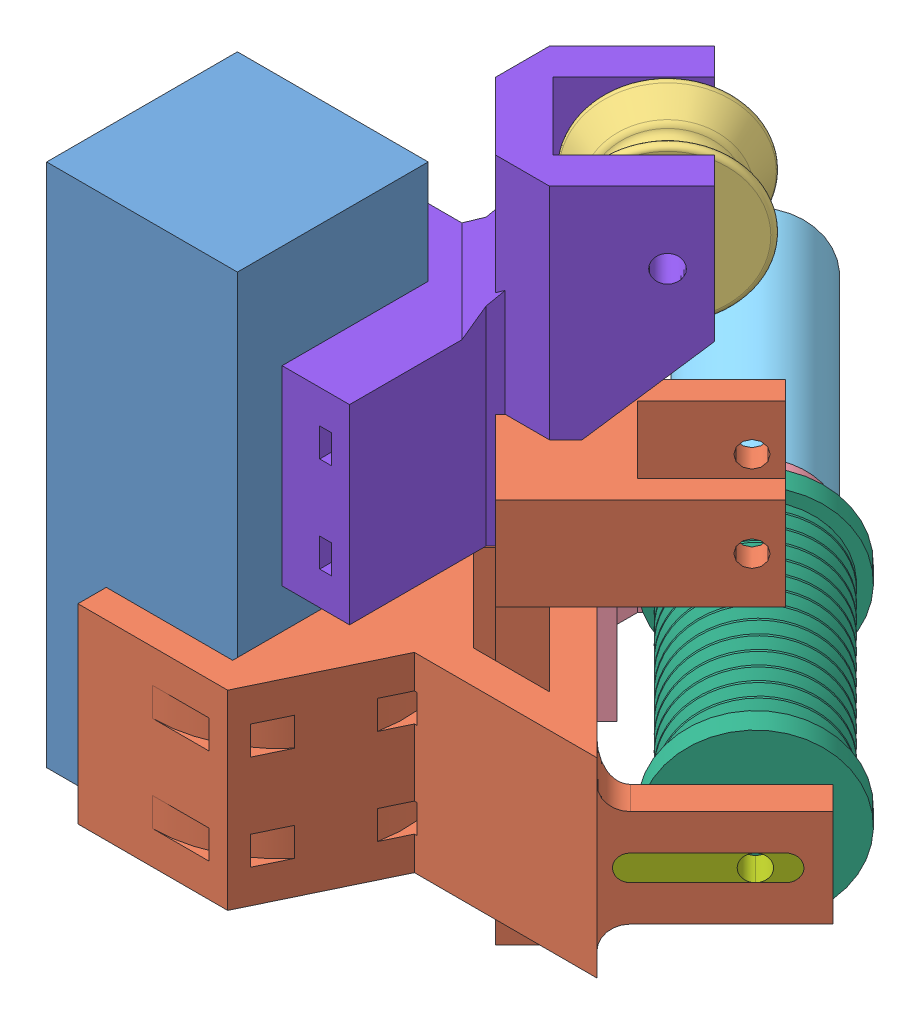
SolidWorks assembly SecondimprvedMechanism, configuration Default. Lengths in mm.
Overall size (306.23 131.11 265.8).
8 component instances, 8 part files, 15 mates.
Components (placement in the parent):
- tableLeg-1: tableLeg [Default] at (50.0377 26.8176 100.477) size (40 110 40)
- square With wire directionalSmaller SecondSupport-1: square With wire directionalSmaller SecondSupport [Default] at (43.5377 46.8176 100.977) size (298.83 105.47 258.03)
- Improvedpulley-1: Improvedpulley [Default] at (89.1192 130.1429 49.3747) x (0.707107 0 0.707107) z (-0.466203 0.751871 0.466203) size (18 32.63 32.63)
- braket-1: braket [Default] at (73.443 44.8547 48.5147) x (0.707107 0 0.707107) z (0 1 0) size (34 36.5 26)
- DC MOTOR-1: DC MOTOR [Default] at (33.1379 44.8547 -25.0244) x (0.5 -0.707107 -0.5) z (-0.5 -0.707107 0.5) size (25 76 25)
- threaded_cable_retractor-1: threaded_cable_retractor [Default] at (72.5744 44.8547 14.412) x (-0.65509 -0.37645 0.65509) z (-0.266191 0.926437 0.266191) size (35 148 35)
- keyForHolder-1: keyForHolder [Default] at (124.4911 46.8176 92.4917) x (0 -1 0) z (-0.707107 0 0.707107) size (5.4 7 28.4)
- pulleySupport-1: pulleySupport [Default] at (145.0377 115.1429 5.477) size (83.77 70 83.77)
Mates (geometry in assembly coordinates):
- Coincident1: coincident anti-aligned: plane of tableLeg-1 through (30.0377 136.8176 80.477) normal (0 0 -1); plane of square With wire directionalSmaller SecondSupport-1 through (70.0377 16.8176 80.477) normal (0 0 1)
- Coincident2: coincident anti-aligned: plane of tableLeg-1 through (70.0377 136.8176 80.477) normal (1 0 0); plane of square With wire directionalSmaller SecondSupport-1 through (70.0377 16.8176 80.477) normal (-1 0 0)
- Coincident3: coincident aligned: plane of tableLeg-1 through (50.0377 26.8176 100.477) normal (0 -1 0); plane of square With wire directionalSmaller SecondSupport-1 through (43.5377 26.8176 100.977) normal (0 -1 0)
- Coincident4: coincident anti-aligned: plane of square With wire directionalSmaller SecondSupport-1 through (125.9053 26.8176 100.977) normal (0.707107 0 -0.707107); plane of braket-1 through (73.443 44.8547 48.5147) normal (-0.707107 0 0.707107)
- Parallel1: parallel aligned: plane of square With wire directionalSmaller SecondSupport-1 through (43.5377 26.8176 100.977) normal (0 -1 0); plane of braket-1 through (64.6042 31.8547 35.4332) normal (0 -1 0)
- Coincident6: coincident anti-aligned: plane of braket-1 through (64.6042 31.8547 35.4332) normal (-0.707107 0 -0.707107); plane of DC MOTOR-1 through (79.0999 44.8547 20.9376) normal (0.707107 0 0.707107)
- Concentric2: concentric aligned: cylinder of braket-1 through (102.788 44.8547 44.6256) axis (-0.707107 0 -0.707107) radius 4; cylinder of DC MOTOR-1 through (86.8781 44.8547 28.7157) axis (-0.707107 0 -0.707107) radius 2
- Concentric3: concentric aligned: cylinder of DC MOTOR-1 through (86.8781 44.8547 28.7157) axis (-0.707107 0 -0.707107) radius 2; cylinder of threaded_cable_retractor-1 through (85.3023 44.8547 27.14) axis (-0.707107 0 -0.707107) radius 10
- Concentric4: concentric anti-aligned: cylinder of square With wire directionalSmaller SecondSupport-1 through (115.2987 46.8176 83.2993) axis (0.707107 0 0.707107) radius 2.7; cylinder of keyForHolder-1 through (129.4408 46.8176 97.4414) axis (-0.707107 0 -0.707107) radius 2.7
- Coincident7: coincident anti-aligned: plane of square With wire directionalSmaller SecondSupport-1 through (115.2987 44.1176 83.2993) normal (0 1 0); plane of keyForHolder-1 through (129.4408 44.1176 97.4414) normal (0 -1 0)
- Coincident8: coincident aligned: plane of square With wire directionalSmaller SecondSupport-1 through (150.654 57.0269 76.2282) normal (0.707107 0 0.707107); plane of keyForHolder-1 through (129.4408 46.8176 97.4414) normal (0.707107 0 0.707107)
- Coincident9: coincident anti-aligned: plane of tableLeg-1 through (30.0377 136.8176 80.477) normal (0 0 -1); plane of pulleySupport-1 through (70.0377 75.1429 80.477) normal (0 0 1)
- Coincident10: coincident anti-aligned: plane of tableLeg-1 through (70.0377 136.8176 80.477) normal (1 0 0); plane of pulleySupport-1 through (70.0377 75.1429 111.1096) normal (-1 0 0)
- Concentric5: concentric aligned: cylinder of Improvedpulley-1 through (89.1192 130.1429 49.3747) axis (0.707107 0 0.707107) radius 2.7; cylinder of pulleySupport-1 through (61.8956 130.1429 22.1511) axis (0.707107 0 0.707107) radius 2.8
- Distance1: distance = 1.5 mm anti-aligned: plane of Improvedpulley-1 through (89.1192 130.1429 49.3747) normal (-0.707107 0 -0.707107); plane of pulleySupport-1 through (76.0377 145.1429 60.3348) normal (0.707107 0 0.707107)
